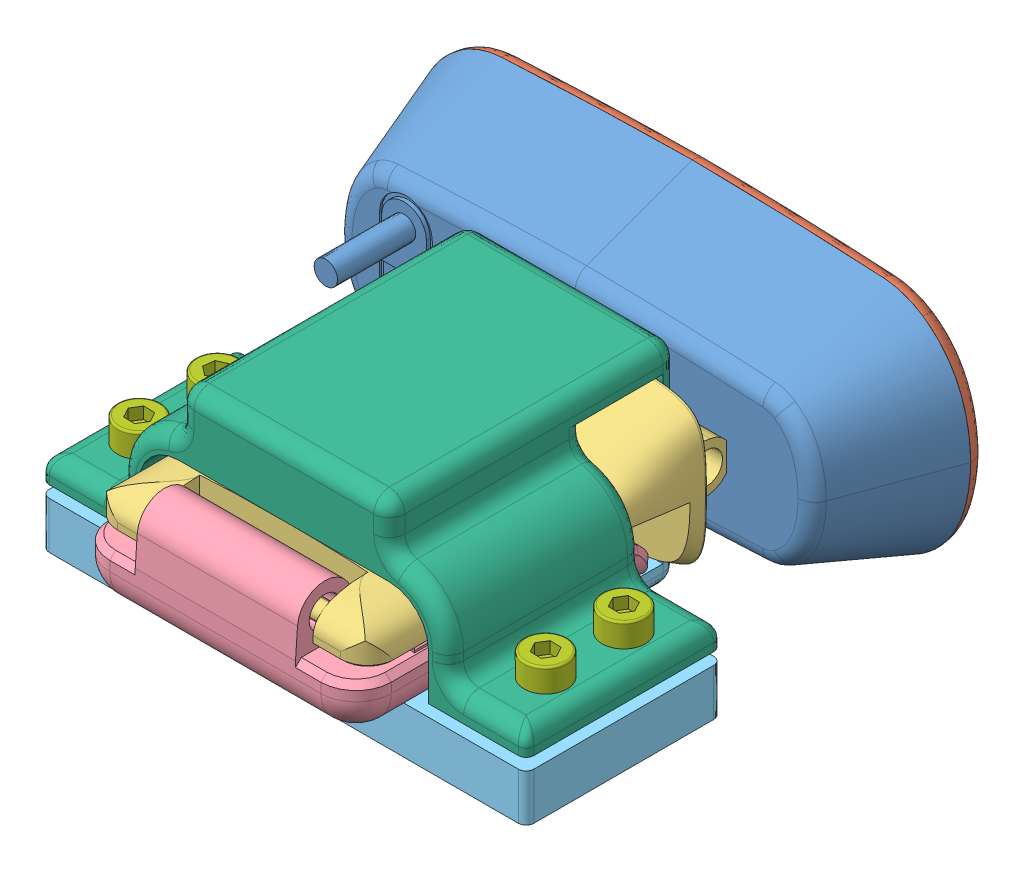
SolidWorks assembly cam-c310-monte, configuration Défaut. Lengths in mm.
Overall size (71.5 31.65 69.48).
15 component instances, 8 part files, 28 mates.
Components (placement in the parent):
- c310-1: c310 [Défaut] at (-9.9235 -1.8504 -19.2289) size (71.5 31.65 69.48)
  - c310-corps-1: c310-corps [Default] at (1.7129 6.6622 61.3001) size (71.27 31.35 30.56)
  - c310-cache-1: c310-cache [Default] at (1.7129 6.6622 59.0501) x (-1 0 0) z (0 0 -1) size (71.5 31.65 2.5)
  - clip-1-1: clip-1 [Default] at (4.1303 6.6622 81.7235) x (-1 0 0) z (0 0 1) size (43.19 23.62 48.27)
  - clip-2-1: clip-2 [Default] at (4.8803 2.4122 105.5985) x (-1 0 0) z (0 0 -1) size (36 14.88 39.47)
- cam-mount-1-1: cam-mount-1 [Défaut] at (-5.0432 -8.6882 84.9946) x (1 0 0) z (0 0 1) size (62 8 37)
- cam-mount-2-1: cam-mount-2 [Défaut] at (-5.0432 -1.1855 72.4946) x (1 0 0) z (0 0 1) size (62 19.5 37)
- vis-chc-1: vis-chc [Vis CHC M3x10] at (20.9537 1.8145 89.9946) x (1 0 0) z (0 0 1) size (5.5 13 5.5)
- vis-chc-2: vis-chc [Vis CHC M3x10] at (20.9537 1.8145 79.9946) x (1 0 0) z (0 0 1) size (5.5 13 5.5)
- ecrou-h-1: ecrou-h [6012 HU M3] at (20.9537 -5.6882 79.9946) x (0.5 0 -0.866025) z (0.866025 0 0.5) size (5.5 2.4 6.35)
- vis-chc-3: vis-chc [Vis CHC M3x10] at (-31.0432 1.8145 89.9946) x (0.999999 0 -0.001191) z (0.001191 0 0.999999) size (5.5 13 5.5)
- vis-chc-4: vis-chc [Vis CHC M3x10] at (-31.0432 1.8145 79.9946) x (0.814665 0 0.579932) z (-0.579932 0 0.814665) size (5.5 13 5.5)
- ecrou-h-2: ecrou-h [6012 HU M3] at (20.9537 -5.6882 89.9946) x (0.5 0 -0.866025) z (0.866025 0 0.5) size (5.5 2.4 6.35)
- ecrou-h-3: ecrou-h [6012 HU M3] at (-31.0432 -5.6882 89.9946) x (0.5 0 -0.866025) z (0.866025 0 0.5) size (5.5 2.4 6.35)
- ecrou-h-4: ecrou-h [6012 HU M3] at (-31.0432 -5.6882 79.9946) x (0.5 0 0.866025) z (-0.866025 0 0.5) size (5.5 2.4 6.35)
Mates (geometry in assembly coordinates):
- Coïncidente6: coincident: line of c310-1/clip-2-1 through (-18.5432 -2.6882 76.4946) axis (1 0 0); plane of mount-1 through (-5.0432 -2.6882 84.9946) normal (0 1 0)
- Coïncidente7: coincident: plane of c310-1/clip-2-1 through (-23.0432 -2.6882 86.3696) normal (0 -1 0); line of mount-1 through (-35.0432 -2.6882 97.4946) axis (1 0 0)
- Parallèle7: parallel anti-aligned: plane of mount-1 through (-5.0432 -2.6882 84.9946) normal (0 1 0); plane of mount-2-1 through (-23.5432 -1.1855 97.4946) normal (0 -1 0)
- Parallèle8: parallel aligned: plane of mount-1 through (-36.0432 -2.6882 97.4946) normal (0 0 1); plane of mount-2-1 through (8.4568 4.8118 97.4946) normal (0 0 1)
- Distance8: distance = 0.5 mm: line of c310-1/clip-2-1 through (-23.0432 1.8118 101.7446) axis (0 1 0); plane of mount-2-1 through (-23.5432 -1.1855 97.4946) normal (1 0 0)
- Coïncidente12: coincident aligned: plane of mount-1 through (-36.0432 -2.6882 97.4946) normal (-1 0 0); plane of mount-2-1 through (-36.0432 -1.1855 72.4946) normal (-1 0 0)
- Coïncidente13: coincident aligned: plane of mount-1 through (-36.0432 -2.6882 72.4946) normal (0 0 -1); plane of mount-2-1 through (8.4568 4.8118 72.4946) normal (0 0 -1)
- Coaxiale1: concentric aligned: cylinder of mount-2-1 through (20.9537 -1.1865 89.9946) axis (0 1 0) radius 1.6; cylinder of vis-chc-1 through (20.9537 -8.1855 89.9946) axis (0 1 0) radius 1.5
- Coaxiale3: concentric aligned: cylinder of mount-2-1 through (20.9537 -1.1865 79.9946) axis (0 1 0) radius 1.6; cylinder of vis-chc-2 through (20.9537 -8.1855 79.9946) axis (0 1 0) radius 1.5
- Coïncidente14: coincident anti-aligned: plane of mount-2-1 through (25.9568 1.8145 97.4946) normal (0 1 0); plane of vis-chc-2 through (20.9537 1.8145 79.9946) normal (0 -1 0)
- Coïncidente15: coincident anti-aligned: plane of mount-2-1 through (25.9568 1.8145 97.4946) normal (0 1 0); plane of vis-chc-1 through (20.9537 1.8145 89.9946) normal (0 -1 0)
- Coaxiale4: concentric aligned: cylinder of vis-chc-2 through (20.9537 -8.1855 79.9946) axis (0 1 0) radius 1.5; cylinder of ecrou-h-1 through (20.9537 -8.0882 79.9946) axis (0 1 0) radius 1.2295
- Coïncidente21: coincident: point of c310-1/clip-1-1; line of mount-2-1 through (-18.5432 9.8118 72.4946) axis (1 0 0)
- Coïncidente22: coincident anti-aligned: plane of mount-1 through (-5.0432 -5.6882 84.9946) normal (0 -1 0); plane of ecrou-h-1 through (20.9537 -5.6882 76.8192) normal (0 1 0)
- Parallèle11: parallel anti-aligned: plane of mount-1 through (20.9568 -5.6882 76.4946) normal (-0.5 0 0.866025); plane of ecrou-h-1 through (23.7037 -8.0882 78.4069) normal (0.5 0 -0.866025)
- Coaxiale5: concentric aligned: cylinder of mount-2-1 through (-31.0432 -1.1865 79.9946) axis (0 1 0) radius 1.6; cylinder of vis-chc-4 through (-31.0432 -8.1855 79.9946) axis (0 1 0) radius 1.5
- Coaxiale6: concentric aligned: cylinder of mount-2-1 through (-31.0432 -1.1865 89.9946) axis (0 1 0) radius 1.6; cylinder of vis-chc-3 through (-31.0432 -8.1855 89.9946) axis (0 1 0) radius 1.5
- Coïncidente24: coincident anti-aligned: plane of mount-2-1 through (-36.0432 1.8145 72.4946) normal (0 1 0); plane of vis-chc-3 through (-31.0432 1.8145 89.9946) normal (0 -1 0)
- Coïncidente25: coincident anti-aligned: plane of mount-2-1 through (-36.0432 1.8145 72.4946) normal (0 1 0); plane of vis-chc-4 through (-31.0432 1.8145 79.9946) normal (0 -1 0)
- Coaxiale7: concentric aligned: cylinder of vis-chc-4 through (-31.0432 -8.1855 79.9946) axis (0 1 0) radius 1.5; cylinder of ecrou-h-4 through (-31.0432 -8.0882 79.9946) axis (0 1 0) radius 1.2295
- Coaxiale8: concentric aligned: cylinder of vis-chc-3 through (-31.0432 -8.1855 89.9946) axis (0 1 0) radius 1.5; cylinder of ecrou-h-3 through (-31.0432 -8.0882 89.9946) axis (0 1 0) radius 1.2295
- Coaxiale10: concentric aligned: cylinder of vis-chc-1 through (20.9537 -8.1855 89.9946) axis (0 1 0) radius 1.5; cylinder of ecrou-h-2 through (20.9537 -8.0882 89.9946) axis (0 1 0) radius 1.2295
- Coïncidente26: coincident anti-aligned: plane of mount-1 through (-5.0432 -5.6882 84.9946) normal (0 -1 0); plane of ecrou-h-2 through (20.9537 -5.6882 86.8192) normal (0 1 0)
- Parallèle12: parallel anti-aligned: plane of mount-1 through (23.9879 -5.6882 88.2446) normal (-1 0 0); plane of ecrou-h-2 through (23.7037 -8.0882 91.5824) normal (1 0 0)
- Parallèle13: parallel anti-aligned: plane of mount-1 through (-34.0743 -5.6882 91.7446) normal (1 0 0); plane of ecrou-h-3 through (-33.7932 -8.0882 88.4069) normal (-1 0 0)
- Coïncidente30: coincident anti-aligned: plane of mount-1 through (-5.0432 -5.6882 84.9946) normal (0 -1 0); plane of ecrou-h-3 through (-31.0432 -5.6882 86.8192) normal (0 1 0)
- Coïncidente31: coincident anti-aligned: plane of mount-1 through (-5.0432 -5.6882 84.9946) normal (0 -1 0); plane of ecrou-h-4 through (-28.2932 -5.6882 81.5824) normal (0 1 0)
- Parallèle14: parallel anti-aligned: plane of mount-1 through (-31.0432 -5.6882 83.4946) normal (0.5 0 -0.866025); plane of ecrou-h-4 through (-33.7932 -8.0882 81.5824) normal (-0.5 0 0.866025)
